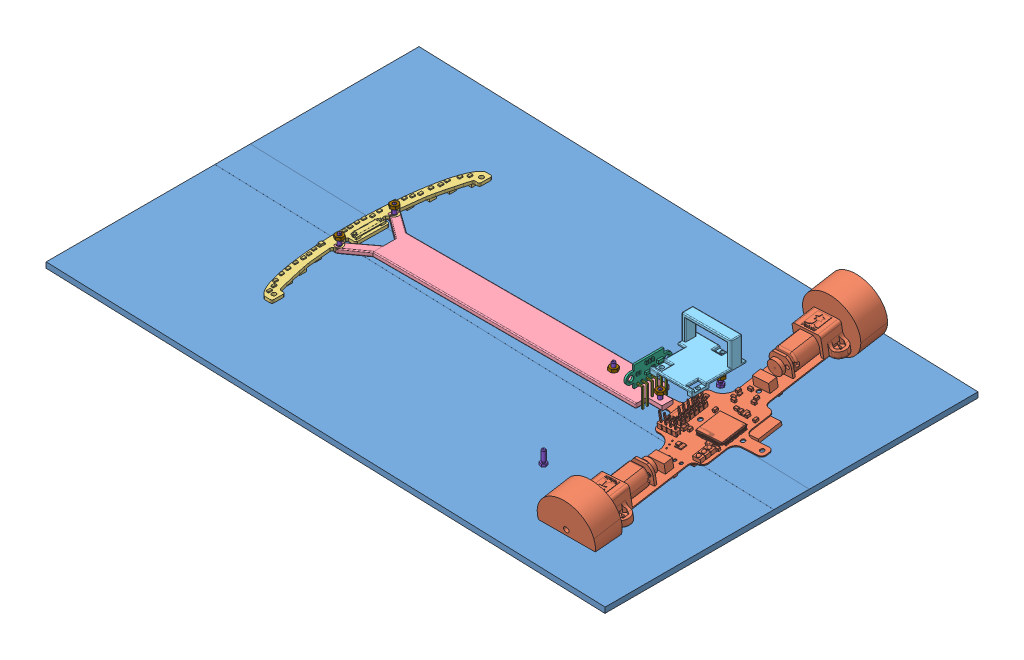
SolidWorks assembly GeneralAssembly, configuration Domyślna. Lengths in mm.
Overall size (299.92 74.6 200).
24 component instances, 9 part files, 5 mates.
Components (placement in the parent):
- TrackPartSimulation-1: TrackPartSimulation [Domyślna] at (55.4335 -15.3279 -55.8665) x (-0.999391 0.034899 0) z (0.034899 0.999391 0) size (300 200 3.02)
- LF_UltraLight_BluClassic.step-1: LF_UltraLight_BluClassic.step [Default] at (4.0323 -2.1795 41.5184) x (-0.034637 0.129297 -0.991001) z (-0.031975 0.990945 0.130407) size (163.88 63.7 30)
- LF_LightLineSensorBoard.step-1: LF_LightLineSensorBoard.step [Default] at (-172.9136 -0.6011 43.9643) x (0.011992 0 -0.999928) z (0 1 0) size (117 15.05 4.87)
- LF_MB_SB_Connector-1: LF_MB_SB_Connector [Domyślna] at origin size (163.88 3.55 34.6)
- BatteryHolder-2: BatteryHolder [Domyślna] at (6.0255 -124.1973 51.0643) x (0 0 -1) z (0 1 0) size (28.98 26.47 16)
- vl53l0x.STEP-1: vl53l0x.STEP [Default] at (-20.75 10.5 44.2773) x (0 0 1) z (0 -1 0) size (25 5.04 19.82)
  - vl53l0x_PCB.STEP-1: vl53l0x_PCB.STEP [Default] at origin size (25 3 11)
  - pin_header.STEP-1: pin_header.STEP [Default] at (-6.5 -2.54 4) size (0.64 4.5 10.64)
  - pin_header.STEP-2: pin_header.STEP [Default] at (-3.96 -2.54 4) size (0.64 4.5 10.64)
  - pin_header.STEP-3: pin_header.STEP [Default] at (-1.42 -2.54 4) size (0.64 4.5 10.64)
  - pin_header.STEP-4: pin_header.STEP [Default] at (1.12 -2.54 4) size (0.64 4.5 10.64)
  - pin_header.STEP-5: pin_header.STEP [Default] at (3.66 -2.54 4) size (0.64 4.5 10.64)
  - pin_header.STEP-6: pin_header.STEP [Default] at (6.2 -2.54 4) size (0.64 4.5 10.64)
- hex head tapping screw_am-1: hex head tapping screw_am [HEXTS 2x6X5.2-Indented head-D-N] at (-172.3907 -1.1911 58.7334) x (0 1 0) z (0.840323 0 0.542086) size (7.3 3.02 3.49)
- hex head tapping screw_am-2: hex head tapping screw_am [HEXTS 2x6X5.2-Indented head-D-N] at (-16.4998 -0.3779 105.0837) x (0 1 0) z (-0.970005 0 -0.243086) size (7.3 3.02 3.49)
- hex head tapping screw_am-3: hex head tapping screw_am [HEXTS 2x6X5.2-Indented head-D-N] at (-39.9499 -1.8164 44.1337) x (0 1 0) z (-0.610789 0 0.791793) size (7.3 3.02 3.49)
- hex head tapping screw_am-4: hex head tapping screw_am [HEXTS 2x6X5.2-Indented head-D-N] at (-172.326 -2.1544 29.3335) x (0 1 0) z (-0.355325 0 -0.934743) size (7.3 3.02 3.49)
- hex head tapping screw_am-5: hex head tapping screw_am [HEXTS 2x6X5.2-Indented head-D-N] at (-14.9498 -1.9588 44.1337) x (0 1 0) z (0.352736 0 -0.935723) size (7.3 3.02 3.49)
- hex nut style 1_am-1: hex nut style 1_am [B18.2.4.1M - Hex nut, Style 1,  M2 x 0.4 --D-N] at (-14.9498 3.6874 44.1337) x (-0.713768 0 -0.700383) z (0 1 0) size (4 4.62 1.6)
- hex nut style 1_am-2: hex nut style 1_am [B18.2.4.1M - Hex nut, Style 1,  M2 x 0.4 --D-N] at (-172.326 2.2281 29.3335) x (-0.438112 0 -0.89892) z (0 -1 0) size (4 4.62 1.6)
- hex nut style 1_am-3: hex nut style 1_am [B18.2.4.1M - Hex nut, Style 1,  M2 x 0.4 --D-N] at (-39.9499 1.7145 44.1337) x (0.098093 0 -0.995177) z (0 1 0) size (4 4.62 1.6)
- hex nut style 1_am-4: hex nut style 1_am [B18.2.4.1M - Hex nut, Style 1,  M2 x 0.4 --D-N] at (-172.3907 4.0302 58.7334) x (-0.527455 0 -0.849583) z (0 1 0) size (4 4.62 1.6)
- hex nut style 1_am-5: hex nut style 1_am [B18.2.4.1M - Hex nut, Style 1,  M2 x 0.4 --D-N] at (-5.75 3.6367 20.8335) x (0.709604 0 -0.704601) z (0 1 0) size (4 4.62 1.6)
- hex head tapping screw_am-6: hex head tapping screw_am [HEXTS 2x6X5.2-Indented head-D-N] at (-5.75 -0.4974 20.8335) x (0 1 0) z (0.996912 0 -0.078529) size (7.3 3.02 3.49)
Mates (geometry in assembly coordinates):
- Koncentryczne24: concentric anti-aligned: cylinder of hex head tapping screw_am-3 through (-39.9499 -1.8164 44.1337) axis (0 -1 0) radius 1; cylinder of hex nut style 1_am-3 through (-39.9499 0.1145 44.1337) axis (0 1 0) radius 0.8
- Koncentryczne26: concentric anti-aligned: cylinder of hex head tapping screw_am-5 through (-14.9498 -1.9588 44.1337) axis (0 -1 0) radius 1; cylinder of hex nut style 1_am-1 through (-14.9498 2.0874 44.1337) axis (0 1 0) radius 0.8
- Wspólnie29: coincident anti-aligned: cylinder of hex head tapping screw_am-1 through (-172.3907 -1.1911 58.7334) axis (0 -1 0) radius 1; circle of hex nut style 1_am-4
- Koncentryczne30: concentric aligned: circle of hex head tapping screw_am-4; circle of hex nut style 1_am-2
- Koncentryczne36: concentric anti-aligned: cylinder of hex nut style 1_am-5 through (-5.75 2.0367 20.8335) axis (0 1 0) radius 0.8; cylinder of hex head tapping screw_am-6 through (-5.75 -0.4974 20.8335) axis (0 -1 0) radius 1
